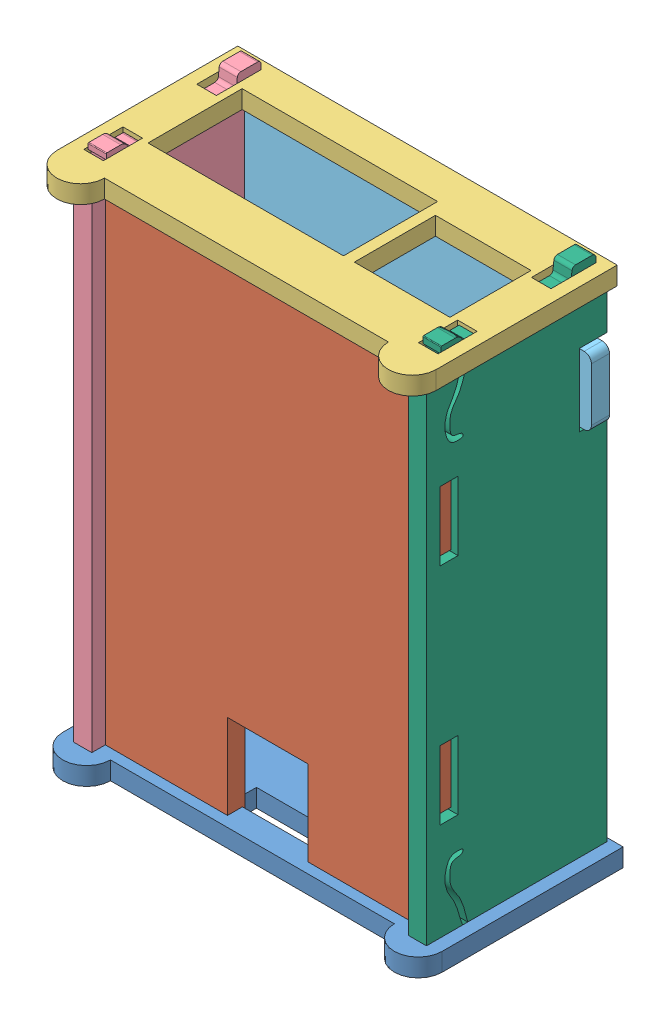
SolidWorks assembly Assembled, configuration Default. Lengths in mm.
Overall size (66.55 95.02 36.98).
6 component instances, 6 part files, 15 mates.
Components (placement in the parent):
- Back-1: Back [Default] at (22.9142 8.4108 66.8035) size (66.55 3.17 35.94)
- Base-1: Base [Default] at (22.3554 54.4102 80.8497) x (0 -1 0) z (1 0 0) size (86.36 3.05 60.96)
- Front-1: Front [Default] at (22.9142 100.4858 67.8449) x (-1 0 0) z (0 0 1) size (66.55 3.17 35.94)
- Left-1: Left [Default] at (-4.721 54.4483 67.4004) x (0 1 0) z (0 0 1) size (95.02 3.17 31.62)
- Top-1: Top [Default] at (23.219 54.6134 53.2399) x (0 -1 0) z (-1 0 0) size (85.6 3.17 65.79)
- Right-1: Right [Default] at (53.9784 54.4483 67.4004) x (0 1 0) z (0 0 1) size (95.02 3.17 31.62)
Mates (geometry in assembly coordinates):
- Coincident24: coincident anti-aligned: plane of Front-1 through (51.9972 97.3108 83.7199) normal (0 -1 0); plane of Left-1 through (-7.896 97.3108 54.5099) normal (0 1 0)
- Coincident25: coincident anti-aligned: plane of Front-1 through (-8.15 97.3108 54.5099) normal (0 0 1); plane of Left-1 through (-7.896 97.3108 54.5099) normal (0 0 -1)
- Coincident26: coincident anti-aligned: plane of Front-1 through (-4.721 97.3108 54.5099) normal (-1 0 0); plane of Left-1 through (-4.721 89.5638 52.2239) normal (1 0 0)
- Coincident29: coincident anti-aligned: plane of Left-1 through (-7.896 88.9288 56.4149) normal (0 0 -1); plane of Top-1 through (-8.404 78.3116 56.4149) normal (0 0 1)
- Coincident30: coincident anti-aligned: plane of Left-1 through (-7.896 88.9288 52.2239) normal (0 -1 0); plane of Top-1 through (-4.721 88.9288 56.4149) normal (0 1 0)
- Coincident31: coincident anti-aligned: plane of Left-1 through (-4.721 89.5638 52.2239) normal (1 0 0); plane of Top-1 through (-4.721 77.0416 56.4149) normal (-1 0 0)
- Coincident35: coincident anti-aligned: plane of Front-1 through (53.9784 97.3108 54.5099) normal (0 0 1); plane of Right-1 through (50.8034 97.3108 54.5099) normal (0 0 -1)
- Coincident36: coincident anti-aligned: plane of Front-1 through (53.9784 97.3108 54.5099) normal (-1 0 0); plane of Right-1 through (53.9784 7.5726 54.1289) normal (1 0 0)
- Coincident37: coincident anti-aligned: plane of Front-1 through (51.9972 97.3108 83.7199) normal (0 -1 0); plane of Right-1 through (50.8034 97.3108 54.5099) normal (0 1 0)
- Coincident38: coincident anti-aligned: plane of Back-1 through (-6.1688 11.5858 82.6785) normal (0 1 0); plane of Right-1 through (50.8034 11.5858 73.4329) normal (0 -1 0)
- Coincident39: coincident anti-aligned: plane of Back-1 through (53.9784 11.5858 80.1385) normal (0 0 -1); plane of Right-1 through (50.8034 8.6648 80.1385) normal (0 0 1)
- Coincident40: coincident anti-aligned: plane of Back-1 through (53.9784 11.5858 73.2805) normal (-1 0 0); plane of Right-1 through (53.9784 7.5726 54.1289) normal (1 0 0)
- Coincident41: coincident anti-aligned: plane of Base-1 through (50.8034 54.4102 77.8017) normal (1 0 0); plane of Right-1 through (50.8034 7.5726 54.1289) normal (-1 0 0)
- Coincident42: coincident anti-aligned: plane of Base-1 through (22.3554 54.4102 80.8497) normal (0 0 1); plane of Right-1 through (50.8034 68.1008 80.8497) normal (0 0 -1)
- Coincident43: coincident anti-aligned: plane of Base-1 through (22.3554 80.1658 77.8017) normal (0 1 0); plane of Right-1 through (50.8034 80.1658 80.8497) normal (0 -1 0)
